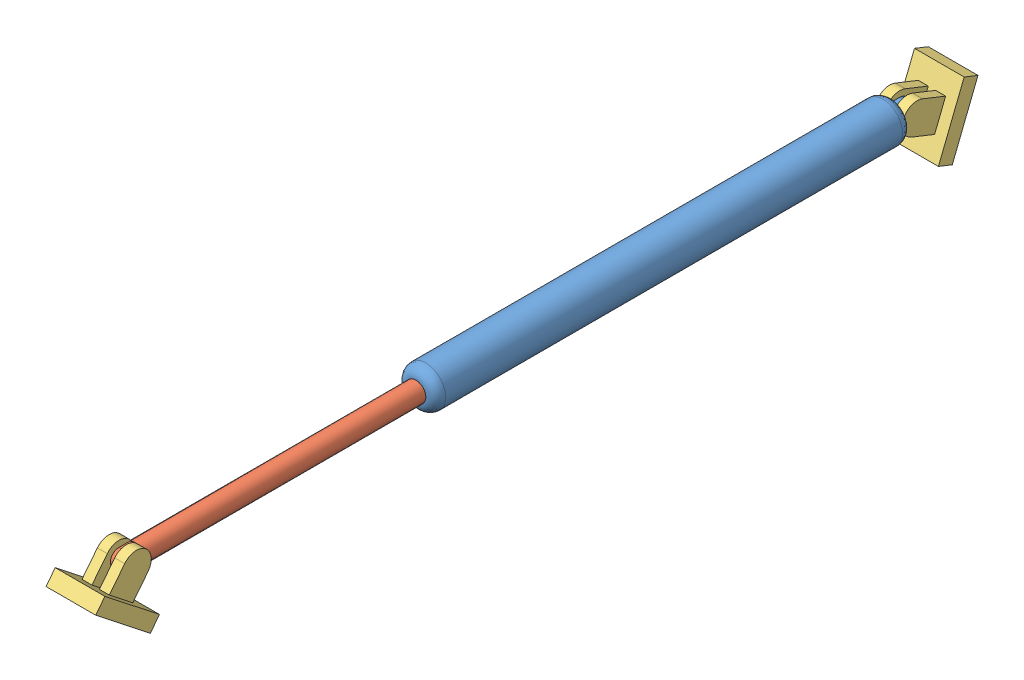
SolidWorks assembly piston, configuration Default. Lengths in mm.
Overall size (16.19 28.94 281.69).
4 component instances, 3 part files, 0 mates.
Components (placement in the parent):
- piston_outer-1-1: piston_outer-1 [Default] at origin size (12.7 12.7 158.75)
- piston core-1-1: piston core-1 [Default] at (0 0 89.8291) x (-1 0 0) z (0 0 1) size (6.35 6.35 158.75)
- piston mount bracket-1-1: piston mount bracket-1 [Default] at (0 -4.6976 -91.406) x (-1 0 0) z (0 0.369887 0.929077) size (15.88 22.23 17.46)
- piston mount bracket-1-2: piston mount bracket-1 [Default] at (-0.3174 -9.9795 177.44) x (-1 0 0) z (0 0.785787 -0.618497) size (15.88 22.23 17.46)
